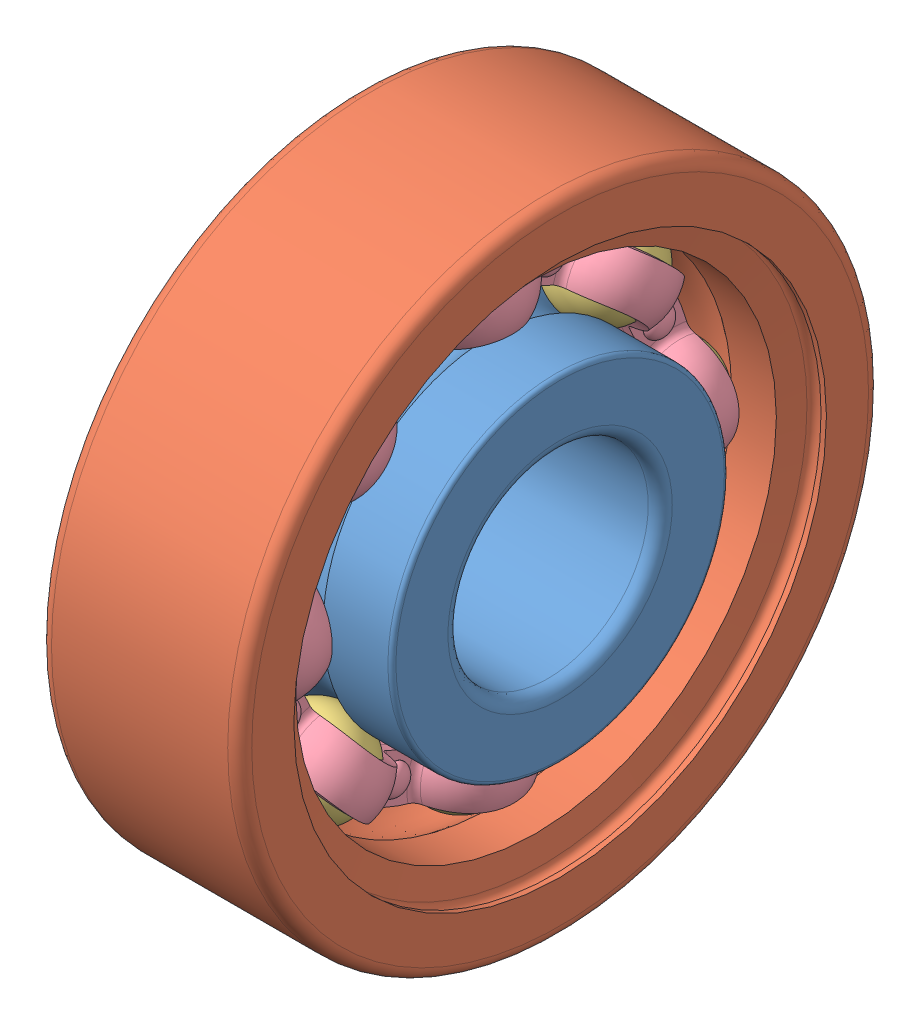
SolidWorks assembly SKF 625, configuration SKF 625. Lengths in mm.
Overall size (5 16 16).
11 component instances, 4 part files, 4 mates.
Components (placement in the parent):
- SKF 625 Inner Race^SKF 625-1: SKF 625 Inner Race^SKF 625 [Default] at origin size (5 8.4 8.4) (virtual)
- SKF 625 Outer Race^SKF 625-1: SKF 625 Outer Race^SKF 625 [Default] at origin size (5 16 16) (virtual)
- SKF 625 Ball^SKF 625-1: SKF 625 Ball^SKF 625 [Default] at origin size (2.38 2.38 2.38) (virtual)
- SKF 625 Ball^SKF 625-2: SKF 625 Ball^SKF 625 [Default] x (1 0 0) z (0 0.707107 0.707107) size (2.38 2.38 2.38) (virtual)
- SKF 625 Ball^SKF 625-3: SKF 625 Ball^SKF 625 [Default] x (1 0 0) z (0 1 0) size (2.38 2.38 2.38) (virtual)
- SKF 625 Ball^SKF 625-4: SKF 625 Ball^SKF 625 [Default] x (1 0 0) z (0 0.707107 -0.707107) size (2.38 2.38 2.38) (virtual)
- SKF 625 Ball^SKF 625-5: SKF 625 Ball^SKF 625 [Default] x (1 0 0) z (0 0 -1) size (2.38 2.38 2.38) (virtual)
- SKF 625 Ball^SKF 625-6: SKF 625 Ball^SKF 625 [Default] x (1 0 0) z (0 -0.707107 -0.707107) size (2.38 2.38 2.38) (virtual)
- SKF 625 Ball^SKF 625-7: SKF 625 Ball^SKF 625 [Default] x (1 0 0) z (0 -1 0) size (2.38 2.38 2.38) (virtual)
- SKF 625 Ball^SKF 625-8: SKF 625 Ball^SKF 625 [Default] x (1 0 0) z (0 -0.707107 0.707107) size (2.38 2.38 2.38) (virtual)
- SKF 625 Cage^SKF 625-1: SKF 625 Cage^SKF 625 [Default] at (2.5 0 0) x (0 0 -1) z (1 0 0) size (11.25 11.25 2.88) (virtual)
Mates (geometry in assembly coordinates):
- InPlace1: in place: plane of SKF 625 Cage^SKF 625-1 through (2.5 0 0) normal (1 0 0); moOrthogonalPlaneRef_w of SKF 625 Cage^SKF 625-1 through (-55 2.5 0) axis (0 0 1); plane of SKF 625 Cage^SKF 625-1 through (2.5 0 0) normal (0 0 -1); unknown of SKF 625 Cage^SKF 625-1
- Coincident1: coincident aligned: plane of SKF 625 Cage^SKF 625-1; plane of assembly
- Coincident2: coincident aligned: plane of SKF 625 Cage^SKF 625-1; moOrthogonalPlaneRef_w of assembly
- Coincident3: coincident anti-aligned: plane of SKF 625 Cage^SKF 625-1 through (2.5 0 0) normal (0 0 -1); moOrthogonalPlaneRef_w of assembly
